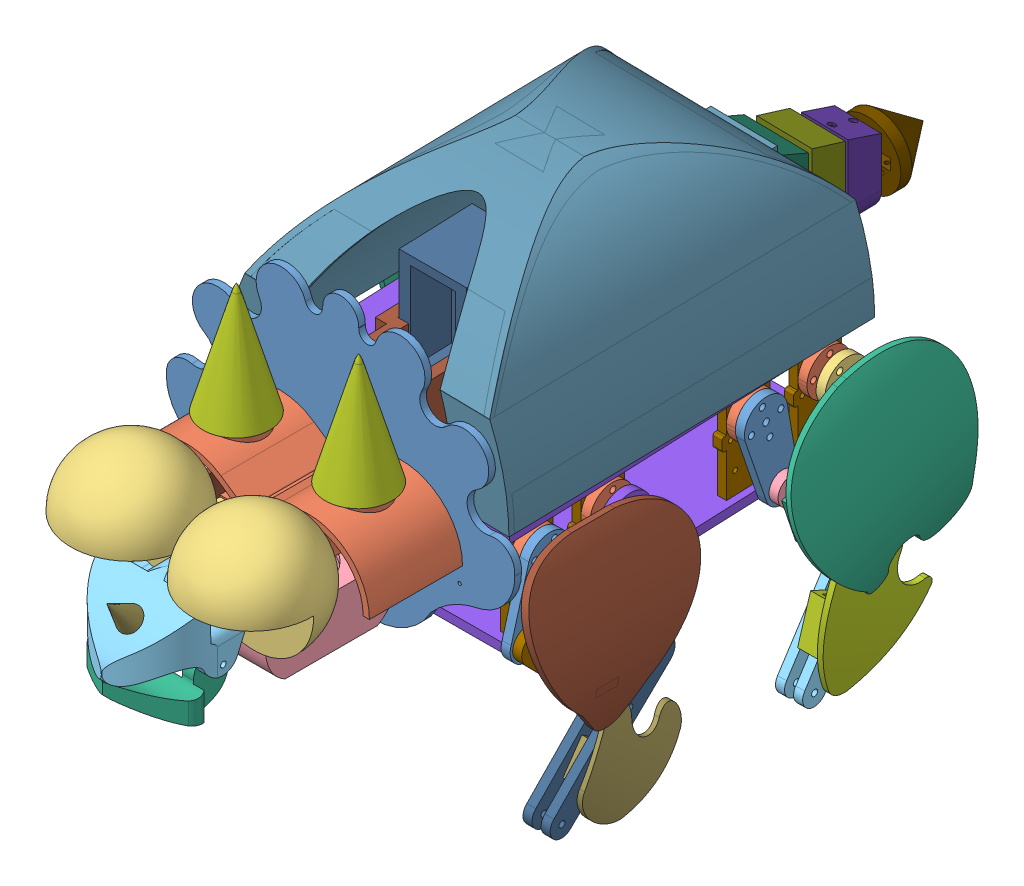
SolidWorks assembly Assem_Triceratops_1, configuration Default. Lengths in mm.
Overall size (206.12 231.26 372.25).
64 component instances, 31 part files, 94 mates.
Components (placement in the parent):
- Part1-1: Part1 [Default] at (0.2171 -2.5315 155.7941) size (157.29 119.12 3.05)
- Part2-2: Part2 [Default] at (0.2171 -2.5315 155.7941) x (1 0 0) z (0 -1 0) size (110 45 44)
- Part3-1: Part3 [Default] at (0.4131 11.3678 225.873) x (1 0 0) z (0 -0.017648 0.999844) size (109.4 54.7 92.35)
- Part33-1: Part33 [Default] at (-1.0816 -38.0168 186.7116) x (1 0 0) z (0 1 0) size (50 59.9 23)
- Part10-1: Part10 [Default] at (-1.0816 -9.9712 225.4964) x (1 0 0) z (0 -0.017648 0.999844) size (55.2 33.44 43.08)
- Part12-1: Part12 [Default] at (-1.0816 -19.417 268.0257) x (-1 0 0) z (0 0 -1) size (50.83 22.71 36.83)
- Part7-1: Part7 [Default] at (27.9121 76.4685 178.3384) x (0 1 0) z (0 0 -1) size (50 30 30)
- Part1^Assem_Triceratops_1-2: Part1^Assem_Triceratops_1 [Default] at origin (virtual)
- Part7-2: Part7 [Default] at (-27.2829 76.4685 178.2941) x (0 1 0) z (-0.725642 0 0.688073) size (50 30 30)
- floor1-1: floor1 [Default] at (2.6068 10.9941 67.8582) x (0.999636 -0.016997 -0.020933) z (-0.017426 -0.999638 -0.020476) size (120 160 4)
- floor1-2: floor1 [Default] at (1.7909 -37.0094 67.875) x (0.999636 -0.016997 -0.020933) z (0.017426 0.999638 0.020476) size (120 160 4)
- rl-2: rl [Default] at (-53.4326 -13.4034 134.5317) x (-0.020578 0.020833 -0.999571) z (0.999636 -0.016997 -0.020933) size (24 48 4)
- rl-3: rl [Default] at (53.8112 -12.5231 0.2857) x (-0.020578 0.020833 -0.999571) z (0.999636 -0.016997 -0.020933) size (24 48 4)
- rl-4: rl [Default] at (-55.4697 -11.3409 35.5742) x (-0.020578 0.020833 -0.999571) z (0.999636 -0.016997 -0.020933) size (24 48 4)
- rl-5: rl [Default] at (56.548 -15.2939 133.2286) x (-0.020578 0.020833 -0.999571) z (0.999636 -0.016997 -0.020933) size (24 48 4)
- rl-7: rl [Default] at (-54.1116 -12.7159 101.5459) x (-0.020578 0.020833 -0.999571) z (0.999636 -0.016997 -0.020933) size (24 48 4)
- rl-8: rl [Default] at (-56.1488 -10.6534 2.5883) x (-0.020578 0.020833 -0.999571) z (0.999636 -0.016997 -0.020933) size (24 48 4)
- Part31(4)-1: Part31(4) [Default] at (3.4199 10.2454 103.7164) x (0.99971 -0.017079 -0.016987) z (0.017426 0.999638 0.020476) size (50 41.81 60)
- Part32-1: Part32 [Default] at (3.8932 16.8337 142.6091) x (-0.99971 0.017079 0.016987) z (0.017426 0.999638 0.020476) size (41 60 25)
- rl-9: rl [Default] at (55.869 -14.6064 100.2428) x (-0.020578 0.020833 -0.999571) z (0.999636 -0.016997 -0.020933) size (24 48 4)
- rl-10: rl [Default] at (54.4903 -13.2106 33.2715) x (-0.020578 0.020833 -0.999571) z (0.999636 -0.016997 -0.020933) size (24 48 4)
- Part11-1: Part11 [Default] at (0.7416 -2.6436 254.4764) x (0 0.731354 0.681998) z (1 0 0) size (15.14 10.4 10.4)
- Part29-1: Part29 [Default] at (1.5464 34.2276 -11.4602) x (0.999848 -0.017426 -0.000178) z (-0.000178 -0.020476 0.99979) size (30 41 30.1)
- Part34-1: Part34 [Default] at (1.7065 12.8985 -16.898) x (0.999848 -0.017426 -0.000178) z (-0.000178 -0.020476 0.99979) size (127.6 88.86 170.09)
- Part23-1: Part23 [Default] at (1.5261 30.4508 -36.5428) x (0.999848 -0.017426 -0.000178) z (-0.000178 -0.020476 0.99979) size (28.94 53.9 25)
- Part28-1: Part28 [Default] at (1.3154 18.5528 -55.401) x (0.999848 -0.017426 -0.000178) z (-0.000178 -0.020476 0.99979) size (25 44.96 38)
- Part24-1: Part24 [Default] at (1.36 21.3031 -73.5551) x (0.999848 -0.017426 -0.000178) z (-0.000178 -0.020476 0.99979) size (20.98 38.44 15)
- Part25-1: Part25 [Default] at (1.2145 13.0472 -83.0306) x (0.000178 0.020476 -0.99979) z (0.017426 0.999638 0.020476) size (35 30 30)
- b4-1: b4 [Default] at (-57.2575 -3.3384 134.7897) x (0.022522 0.099393 0.994793) z (-0.999636 0.016997 0.020933) size (20 47.65 4)
- b5-1: b5 [Default] at (-55.9752 -0.6564 2.7626) x (0.019156 -0.09874 0.994929) z (-0.999636 0.016997 0.020933) size (20 20 4)
- b5-2: b5 [Default] at (-55.2949 -1.3452 35.8094) x (0.021874 0.0572 0.998123) z (-0.999636 0.016997 0.020933) size (20 20 4)
- b5-3: b5 [Default] at (64.0409 -4.7467 100.3105) x (0.021874 0.0572 0.998123) z (-0.999636 0.016997 0.020933) size (20 20 4)
- b5-5: b5 [Default] at (-53.938 -2.7189 101.7202) x (0.019156 -0.09874 0.994929) z (-0.999636 0.016997 0.020933) size (20 20 4)
- b5-6: b5 [Default] at (-53.2589 -3.4064 134.706) x (0.019156 -0.09874 0.994929) z (-0.999636 0.016997 0.020933) size (20 20 4)
- b5-7: b5 [Default] at (64.7187 -5.4329 133.2355) x (0.019156 -0.09874 0.994929) z (-0.999636 0.016997 0.020933) size (20 20 4)
- b5-8: b5 [Default] at (62.6622 -3.3508 33.3393) x (0.021874 0.0572 0.998123) z (-0.999636 0.016997 0.020933) size (20 20 4)
- b5-9: b5 [Default] at (61.9832 -2.6633 0.3534) x (0.021874 0.0572 0.998123) z (-0.999636 0.016997 0.020933) size (20 20 4)
- b4-2: b4 [Default] at (-59.2934 -1.2772 35.8931) x (0.019303 -0.091011 0.995663) z (-0.999636 0.016997 0.020933) size (20 47.65 4)
- b4-3: b4 [Default] at (68.7173 -5.5009 133.1517) x (0.025367 0.329524 0.943806) z (-0.999636 0.016997 0.020933) size (20 47.65 4)
- b4-4: b4 [Default] at (66.6608 -3.4188 33.2555) x (0.01574 -0.262541 0.964792) z (-0.999636 0.016997 0.020933) size (20 47.65 4)
- b3-1: b3 [Default] at (64.7999 -39.3926 -26.3998) x (-0.010037 0.486004 -0.873899) z (0.999636 -0.016997 -0.020933) size (20 68.52 4)
- b3-2: b3 [Default] at (-69.0415 -42.4828 -13.9864) x (-0.015796 0.260035 -0.96547) z (0.999636 -0.016997 -0.020933) size (20 68.52 4)
- b2-1: b2 [Default] at (-69.0709 -63.7103 1.8456) x (-0.006798 0.592372 -0.805636) z (0.999636 -0.016997 -0.020933) size (12.08 64.59 4)
- b2-2: b2 [Default] at (64.7794 -60.4723 -10.2596) x (-0.003188 0.696385 -0.717661) z (0.999636 -0.016997 -0.020933) size (12.08 64.59 4)
- b1-1: b1 [Default] at (68.3252 -106.6339 5.4602) x (-0.026861 -0.559749 -0.828227) z (0.999636 -0.016997 -0.020933) size (13 90 4)
- b1-2: b1 [Default] at (60.3281 -106.4979 5.6276) x (-0.026861 -0.559749 -0.828227) z (0.999636 -0.016997 -0.020933) size (13 90 4)
- b1-3: b1 [Default] at (-65.564 -110.9985 16.6239) x (-0.026667 -0.508195 -0.860829) z (0.999636 -0.016997 -0.020933) size (13 90 4)
- b1-4: b1 [Default] at (-73.5611 -110.8625 16.7914) x (-0.026667 -0.508195 -0.860829) z (0.999636 -0.016997 -0.020933) size (13 90 4)
- Partขาหน้า1-1: Partขาหน้า1 [Default] at (103.6933 -29.1671 6.1585) x (0 -0.317305 0.948324) z (-1 0 0) size (90.6 94.22 33.55)
- Partขาหน้า1-2(2)-1: Partขาหน้า1-2(2) [Default] at (95.4038 -77.2926 -2.5466) x (0 0.414693 0.909961) z (-1 0 0) size (54.04 60.02 20.5)
- Partขาหน้า1-2: Partขาหน้า1 [Default] at (-102.3272 -24.525 5.7291) x (0 0 -1) z (1 0 0) size (90.6 94.22 33.55)
- Partขาหน้า1-2(2)-2: Partขาหน้า1-2(2) [Default] at (-95.8212 -80.9793 4.1305) x (0 -0.358368 -0.93358) z (1 0 0) size (54.04 60.02 20.5)
- f2-1: f2 [Default] at (72.0921 3.1112 96.2367) x (-0.016887 0.210592 -0.977428) z (-0.999636 0.016997 0.020933) size (20 74.52 4)
- f2-2: f2 [Default] at (-61.8804 5.421 98.0019) x (-0.016833 0.213108 -0.976884) z (-0.999636 0.016997 0.020933) size (20 74.52 4)
- f3-2: f3 [Default] at (-67.4532 -78.875 91.4059) x (-0.005231 0.639316 -0.768926) z (0.999636 -0.016997 -0.020933) size (13 70.02 4)
- f3-3: f3 [Default] at (66.6831 -77.3488 94.3482) x (-0.003951 0.675624 -0.737236) z (0.999636 -0.016997 -0.020933) size (13 70.02 4)
- f1-1: f1 [Default] at (-71.5948 -119.0128 117.305) x (-0.026608 -0.495904 -0.86797) z (0.999636 -0.016997 -0.020933) size (13 75.02 4)
- f1-2: f1 [Default] at (-63.5977 -119.1488 117.1375) x (-0.026608 -0.495904 -0.86797) z (0.999636 -0.016997 -0.020933) size (13 75.02 4)
- f1-3: f1 [Default] at (62.8844 -111.294 131.5967) x (-0.026751 -0.722657 -0.690689) z (0.999636 -0.016997 -0.020933) size (13 75.02 4)
- f1-4: f1 [Default] at (70.8815 -111.43 131.4293) x (-0.026751 -0.722657 -0.690689) z (0.999636 -0.016997 -0.020933) size (13 75.02 4)
- Partขา2-1: Partขา2 [Default] at (-99.8977 -88.075 125.9802) x (-0.020933 0.000178 -0.999781) z (0.999636 -0.016997 -0.020933) size (82.69 82.38 31.77)
- Partขา2-2: Partขา2 [Default] at (99.0163 -32.9582 126.1159) x (0 0 1) z (-1 0 0) size (82.69 82.38 31.77)
- Partขา1-2(1)-1: Partขา1-2(1) [Default] at (-68.2015 -71.5859 113.8208) x (0 0.559193 0.829038) z (-1 0 0) size (47.75 46.85 16.68)
- Partขา1-2(1)-2: Partขา1-2(1) [Default] at (72.3234 -78.4813 98.1951) x (0 -0.67559 -0.737277) z (1 0 0) size (47.75 46.85 16.68)
Mates (geometry in assembly coordinates):
- Coincident1: coincident anti-aligned: line of Part1-1 through (55.2171 -2.5315 155.7941) axis (-1 0 0); line of Part2-2 through (52.4171 -2.5315 155.7941) axis (1 0 0)
- Coincident4: coincident anti-aligned: plane of Part2-2 through (10.1631 7.4685 200.7941) normal (-1 0 0); plane of Part3-1 through (10.1631 6.7626 200.7878) normal (1 0 0)
- Concentric4: concentric aligned: circle of Part1-1; circle of Part2-2
- Coincident6: coincident aligned: line of Part2-2 through (-9.7289 7.4685 160.7941) axis (1 0 0); line of Part3-1 through (-9.3369 7.4685 160.7941) axis (1 0 0)
- Coincident14: coincident anti-aligned: circle of Part10-1; circle of Part12-1
- Coincident15: coincident anti-aligned: plane of Part3-1 through (-57.5896 -15.9779 225.3903) normal (0 -0.017648 0.999844); plane of Part10-1 through (-1.0816 -9.9712 225.4964) normal (0 0.017648 -0.999844)
- Parallel7: parallel anti-aligned: plane of Part2-2 through (27.7171 31.4685 178.2941) normal (0 1 0); plane of Part7-1 through (27.9121 31.4685 178.3384) normal (0 -1 0)
- Tangent2: tangent: circle of Part2-2; circle of Part7-1
- Concentric7: concentric anti-aligned: circle of Part2-2; circle of Part7-2
- Coincident17: coincident anti-aligned: plane of Part2-2 through (-27.2829 31.4685 178.2941) normal (0 1 0); plane of Part7-2 through (-27.2829 31.4685 178.2941) normal (0 -1 0)
- Coincident18: coincident anti-aligned: plane of Part31(4)-1 through (-9.9903 85.1266 122.251) normal (0.016632 -0.020766 0.999646); plane of Part32-1 through (14.0243 17.1112 120.4386) normal (-0.016632 0.020766 -0.999646)
- Coincident28: coincident aligned: line of floor1-1 through (57.028 8.6349 136.7188) axis (-0.020578 0.020833 -0.999571); line of rl-5 through (57.028 8.6349 136.7188) axis (-0.020578 0.020833 -0.999571)
- Coincident29: coincident: point of floor1-2; unknown of rl-5
- Coincident33: coincident: unknown of floor1-1; unknown of rl-3
- Coincident34: coincident: unknown of floor1-1; unknown of rl-2
- Coincident35: coincident: unknown of floor1-1; unknown of rl-7
- Coincident36: coincident: unknown of floor1-1; unknown of rl-4
- Coincident37: coincident: unknown of floor1-1; unknown of rl-8
- Coincident40: coincident aligned: line of floor1-2 through (57.3298 -36.5199 -3.2882) axis (-0.999636 0.016997 0.020933); line of rl-3 through (57.3298 -36.5199 -3.2882) axis (-0.999636 0.016997 0.020933)
- Coincident41: coincident: unknown of floor1-2; unknown of rl-8
- Coincident42: coincident: unknown of floor1-2; unknown of rl-4
- Coincident43: coincident: unknown of floor1-2; unknown of rl-7
- Coincident44: coincident: line of floor1-2 through (-49.914 -37.4002 130.9578) axis (-0.999636 0.016997 0.020933); unknown of rl-2
- Concentric10: concentric aligned: circle of floor1-1; circle of Part31(4)-1
- Coincident48: coincident anti-aligned: line of Part31(4)-1 through (19.7396 69.6197 121.4343) axis (-0.017426 -0.999638 -0.020476); line of Part32-1 through (18.8229 17.0292 120.357) axis (0.017426 0.999638 0.020476)
- Coincident49: coincident anti-aligned: line of floor1-2 through (53.3312 -36.4519 -3.2045) axis (0.020578 -0.020833 0.999571); line of rl-3 through (53.4547 -36.5769 2.7929) axis (-0.020578 0.020833 -0.999571)
- Coincident51: coincident anti-aligned: line of floor1-2 through (-51.9512 -35.3377 32.0003) axis (0.020578 -0.020833 0.999571); line of rl-4 through (-51.8277 -35.4627 37.9977) axis (-0.020578 0.020833 -0.999571)
- Coincident53: coincident anti-aligned: line of floor1-2 through (-52.6302 -34.6502 -0.9856) axis (0.020578 -0.020833 0.999571); line of rl-8 through (-52.5068 -34.7752 5.0119) axis (-0.020578 0.020833 -0.999571)
- Coincident58: coincident anti-aligned: line of floor1-1 through (54.8262 10.8641 29.7646) axis (0.020578 -0.020833 0.999571); line of rl-10 through (54.9702 10.7182 36.7616) axis (-0.020578 0.020833 -0.999571)
- Coincident59: coincident: plane of floor1-1 through (1.7757 7.7664 30.7922) normal (0.020578 -0.020833 0.999571); unknown of rl-10
- Coincident61: coincident aligned: line of floor1-1 through (56.3489 9.3224 103.7329) axis (-0.020578 0.020833 -0.999571); line of rl-9 through (56.3489 9.3224 103.7329) axis (-0.020578 0.020833 -0.999571)
- Coincident62: coincident: plane of floor1-1 through (3.2985 6.2247 104.7605) normal (-0.020578 0.020833 -0.999571); unknown of rl-9
- Tangent7: tangent: circle of floor1-1; circle of Part31(4)-1
- Concentric15: concentric anti-aligned: circle of floor1-1; circle of Part29-1
- Parallel17: parallel anti-aligned: plane of Part29-1 through (14.2659 46.9148 -31.2023) normal (0.999848 -0.017426 -0.000178); plane of Part34-1 through (13.7056 12.7917 -21.8991) normal (-0.999848 0.017426 0.000178)
- Coincident70: coincident aligned: line of Part29-1 through (-6.1332 26.8619 -11.6124) axis (0.999848 -0.017426 -0.000178); line of Part23-1 through (-6.0332 26.8601 -11.6124) axis (0.999848 -0.017426 -0.000178)
- Coincident71: coincident anti-aligned: line of Part29-1 through (8.9645 26.5987 -11.6151) axis (0.017426 0.999638 0.020476); line of Part23-1 through (9.3131 46.5915 -11.2056) axis (-0.017426 -0.999638 -0.020476)
- Coincident72: coincident: line of Part34-1 through (13.7056 12.7917 -21.8991) axis (0.017426 0.999638 0.020476); plane of Part23-1 through (-13.0141 30.3971 -21.5433) normal (-0.000178 -0.020476 0.99979)
- Coincident73: coincident aligned: circle of Part23-1; circle of Part28-1
- Coincident74: coincident anti-aligned: circle of Part28-1; circle of Part24-1
- Coincident75: coincident anti-aligned: circle of Part24-1; circle of Part25-1
- Coincident78: coincident anti-aligned: plane of rl-8 through (-56.1488 -10.6534 2.5883) normal (-0.999636 0.016997 0.020933); plane of b5-1 through (-56.5445 -30.5054 -0.1887) normal (0.999636 -0.016997 -0.020933)
- Tangent8: tangent anti-aligned: plane of floor1-1 through (2.5371 6.9955 67.7763) normal (-0.017426 -0.999638 -0.020476); cylinder of b5-1 through (-59.9737 -0.5884 2.8464) axis (0.999636 -0.016997 -0.020933) radius 10
- Coincident79: coincident anti-aligned: plane of rl-4 through (-55.4697 -11.3409 35.5742) normal (-0.999636 0.016997 0.020933); plane of b5-2 through (-55.7679 -31.2917 37.5359) normal (0.999636 -0.016997 -0.020933)
- Tangent9: tangent anti-aligned: plane of floor1-1 through (2.5371 6.9955 67.7763) normal (-0.017426 -0.999638 -0.020476); cylinder of b5-2 through (-59.2934 -1.2772 35.8931) axis (0.999636 -0.016997 -0.020933) radius 10
- Coincident80: coincident aligned: line of rl-4 through (-54.9155 8.4435 45.9794) axis (-0.017426 -0.999638 -0.020476); line of b5-2 through (-55.0761 -0.7732 45.7906) axis (-0.017426 -0.999638 -0.020476)
- Coincident81: coincident anti-aligned: plane of rl-7 through (-54.1116 -12.7159 101.5459) normal (-0.999636 0.016997 0.020933); plane of b5-5 through (-54.5073 -32.5679 98.7688) normal (0.999636 -0.016997 -0.020933)
- Tangent10: tangent anti-aligned: plane of floor1-1 through (2.5371 6.9955 67.7763) normal (-0.017426 -0.999638 -0.020476); cylinder of b5-5 through (-57.9365 -2.6509 101.8039) axis (0.999636 -0.016997 -0.020933) radius 10
- Coincident82: coincident aligned: line of rl-7 through (-53.9689 7.4852 91.9597) axis (-0.017426 -0.999638 -0.020476); line of b5-5 through (-54.1295 -1.7315 91.7709) axis (-0.017426 -0.999638 -0.020476)
- Coincident83: coincident anti-aligned: plane of rl-2 through (-53.4326 -13.4034 134.5317) normal (-0.999636 0.016997 0.020933); plane of b5-6 through (-53.8283 -33.2554 131.7547) normal (0.999636 -0.016997 -0.020933)
- Tangent11: tangent anti-aligned: plane of floor1-1 through (2.5371 6.9955 67.7763) normal (-0.017426 -0.999638 -0.020476); cylinder of b5-6 through (-57.2575 -3.3384 134.7897) axis (0.999636 -0.016997 -0.020933) radius 10
- Coincident84: coincident aligned: line of rl-2 through (-53.2898 6.7977 124.9455) axis (-0.017426 -0.999638 -0.020476); line of b5-6 through (-53.4505 -2.419 124.7567) axis (-0.017426 -0.999638 -0.020476)
- Coincident85: coincident anti-aligned: plane of rl-9 through (59.8675 -14.6744 100.159) normal (0.999636 -0.016997 -0.020933); plane of b5-3 through (59.5694 -34.6252 102.1208) normal (-0.999636 0.016997 0.020933)
- Tangent12: tangent anti-aligned: plane of floor1-1 through (2.5371 6.9955 67.7763) normal (-0.017426 -0.999638 -0.020476); cylinder of b5-3 through (60.0424 -4.6787 100.3943) axis (0.999636 -0.016997 -0.020933) radius 10
- Coincident86: coincident aligned: line of rl-9 through (60.4218 5.11 110.5643) axis (-0.017426 -0.999638 -0.020476); line of b5-3 through (60.2611 -4.1067 110.3755) axis (-0.017426 -0.999638 -0.020476)
- Coincident87: coincident anti-aligned: plane of rl-5 through (60.5466 -15.3619 133.1449) normal (0.999636 -0.016997 -0.020933); plane of b5-7 through (60.1509 -35.214 130.3678) normal (-0.999636 0.016997 0.020933)
- Tangent13: tangent anti-aligned: plane of floor1-1 through (2.5371 6.9955 67.7763) normal (-0.017426 -0.999638 -0.020476); cylinder of b5-7 through (60.7202 -5.3649 133.3192) axis (0.999636 -0.016997 -0.020933) radius 10
- Coincident88: coincident aligned: line of rl-5 through (60.6893 4.8392 123.5587) axis (-0.017426 -0.999638 -0.020476); line of b5-7 through (60.5286 -4.3775 123.3699) axis (-0.017426 -0.999638 -0.020476)
- Coincident89: coincident anti-aligned: plane of rl-10 through (58.4888 -13.2786 33.1878) normal (0.999636 -0.016997 -0.020933); plane of b5-8 through (58.1907 -33.2294 35.1495) normal (-0.999636 0.016997 0.020933)
- Tangent14: tangent anti-aligned: plane of floor1-1 through (2.5371 6.9955 67.7763) normal (-0.017426 -0.999638 -0.020476); cylinder of b5-8 through (58.6637 -3.2828 33.423) axis (0.999636 -0.016997 -0.020933) radius 10
- Coincident90: coincident aligned: line of rl-10 through (59.0431 6.5059 43.593) axis (-0.017426 -0.999638 -0.020476); line of b5-8 through (58.8824 -2.7108 43.4042) axis (-0.017426 -0.999638 -0.020476)
- Tangent15: tangent anti-aligned: plane of floor1-1 through (2.5371 6.9955 67.7763) normal (-0.017426 -0.999638 -0.020476); cylinder of b5-9 through (57.9846 -2.5953 0.4371) axis (0.999636 -0.016997 -0.020933) radius 10
- Coincident91: coincident anti-aligned: plane of rl-3 through (57.8097 -12.5911 0.2019) normal (0.999636 -0.016997 -0.020933); plane of b5-9 through (57.5116 -32.5419 2.1637) normal (-0.999636 0.016997 0.020933)
- Coincident92: coincident aligned: line of rl-3 through (58.364 7.1934 10.6072) axis (-0.017426 -0.999638 -0.020476); line of b5-9 through (58.2034 -2.0233 10.4184) axis (-0.017426 -0.999638 -0.020476)
- Coincident94: coincident aligned: circle of b4-1; circle of b5-6
- Coincident95: coincident aligned: circle of b5-2; circle of b4-2
- Coincident96: coincident aligned: circle of b5-7; circle of b4-3
- Coincident97: coincident aligned: circle of b5-8; circle of b4-4
- Concentric16: concentric anti-aligned: circle of b5-9; circle of b3-1
- Concentric17: concentric anti-aligned: circle of b5-1; circle of b3-2
- Coincident98: coincident anti-aligned: circle of b4-2; circle of b2-1
- Coincident99: coincident anti-aligned: circle of b4-4; circle of b2-2
- Coincident100: coincident aligned: circle of b3-1; circle of b1-1
- Coincident101: coincident aligned: circle of b2-2; circle of b1-1
- Coincident102: coincident aligned: circle of b3-1; circle of b1-2
- Coincident103: coincident aligned: circle of b2-2; circle of b1-2
- Coincident104: coincident aligned: circle of b3-2; circle of b1-3
- Coincident105: coincident aligned: circle of b2-1; circle of b1-3
- Coincident106: coincident aligned: circle of b3-2; circle of b1-4
- Coincident107: coincident aligned: circle of b2-1; circle of b1-4
- Coincident109: coincident aligned: line of rl-8 through (-56.0061 9.5477 -6.9979) axis (-0.017426 -0.999638 -0.020476); line of b5-1 through (-56.1667 0.331 -7.1867) axis (-0.017426 -0.999638 -0.020476)
- Concentric18: concentric aligned: circle of b5-5; circle of f2-2
- Concentric19: concentric aligned: circle of b5-3; circle of f2-1
- Coincident113: coincident anti-aligned: circle of b4-1; circle of f3-2
- Coincident114: coincident anti-aligned: circle of b4-3; circle of f3-3
- Coincident115: coincident anti-aligned: circle of f2-2; circle of f1-1
- Coincident116: coincident aligned: circle of f3-2; circle of f1-1
- Coincident117: coincident anti-aligned: circle of f2-2; circle of f1-2
- Coincident118: coincident aligned: circle of f3-2; circle of f1-2
- Coincident119: coincident anti-aligned: circle of f2-1; circle of f1-3
- Coincident120: coincident aligned: circle of f3-3; circle of f1-3
- Coincident121: coincident anti-aligned: circle of f2-1; circle of f1-4
- Coincident122: coincident aligned: circle of f3-3; circle of f1-4
- Coincident123: coincident anti-aligned: plane of f3-2 through (-67.2395 -77.0156 100.1042) normal (-0.999636 0.016997 0.020933); plane of Partขา2-1 through (-66.9097 -88.6359 125.2894) normal (0.999636 -0.016997 -0.020933)
